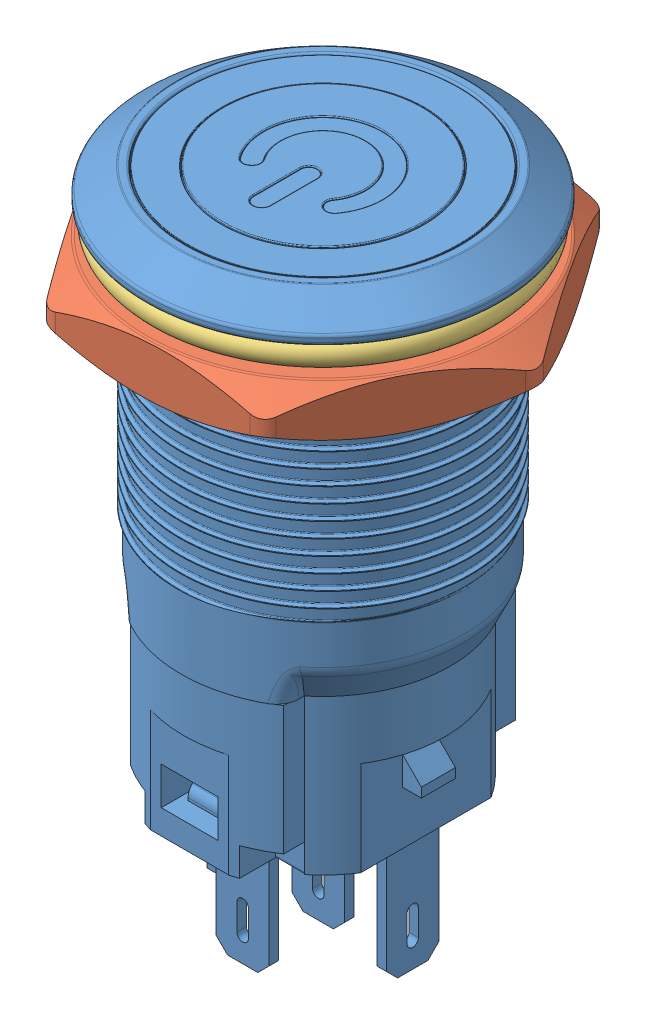
SolidWorks assembly ON_OFF - Button_16mm, configuration Default. Lengths in mm.
Overall size (26.77 34.5 27.92).
3 component instances, 3 part files, 3 mates.
Components (placement in the parent):
- Body-1: Body [Default] at origin size (18.8 34.5 18.8)
- Thread-1: Thread [Default] at (0 -4.2912 0) x (0.456141 0 -0.889908) z (0.889908 0 0.456141) size (21.63 2.8 19)
- O-Ring-1: O-Ring [Default] at (0 -0.7221 0) x (0.957514 0 -0.288386) z (0.288386 0 0.957514) size (18.4 1.4 18.4)
Mates (geometry in assembly coordinates):
- Concentric1: concentric aligned: cylinder of Body-1 through (0 -16.3 0) axis (0 1 0) radius 7.5; circle of Thread-1
- LimitDistance1: limit distance = 1.4912 mm anti-aligned: plane of Body-1 through (0 0 0) normal (0 -1 0); plane of Thread-1 through (0 -1.4912 0) normal (0 1 0)
- Concentric2: concentric aligned: line of Body-1; line of O-Ring-1 through (3.5934 0 -0.7221) axis (0 0 1)
